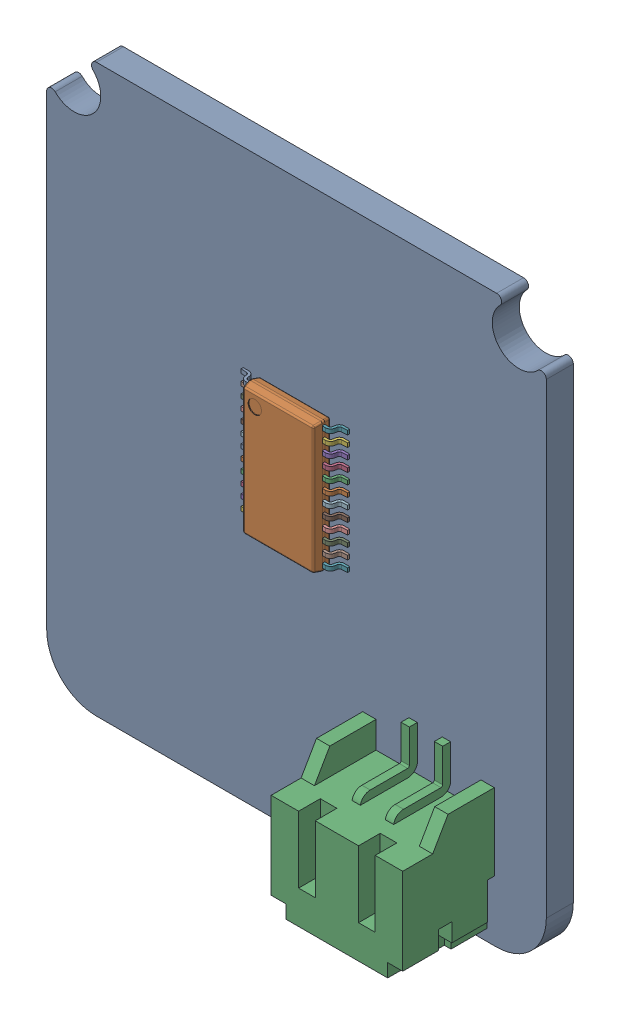
SolidWorks assembly Firefly-mini-expansion, configuration Default. Lengths in mm.
Overall size (30 34 8.46).
4 component instances, 4 part files, 0 mates.
Components (placement in the parent):
- Firefly-mini-expansion_BOARD-1: Firefly-mini-expansion_BOARD [Default] at origin size (30 34 1.62)
- TI-PW24_M_CMP-015-00009-1-1: TI-PW24_M_CMP-015-00009-1 [Default] at (25 44.831 1.594) size (6.4 7.8 1.13)
- JST-_S2B-PH-SM4-TB(LF)(SN)-2_V_CMP-002-00031-2-1: JST-_S2B-PH-SM4-TB(LF)(SN)-2_V_CMP-002-00031-2 [Default] at (33 30.5 1.594) size (7.9 8.6 5.6)
- FP-DF40C-40DP-0_4V_51-MFG_CMP-002-00095-1-1: FP-DF40C-40DP-0_4V_51-MFG_CMP-002-00095-1 [Default] at (25 30 0.0254) x (1 0 0) z (0 0 -1) size (9.53 2.97 1.29)
